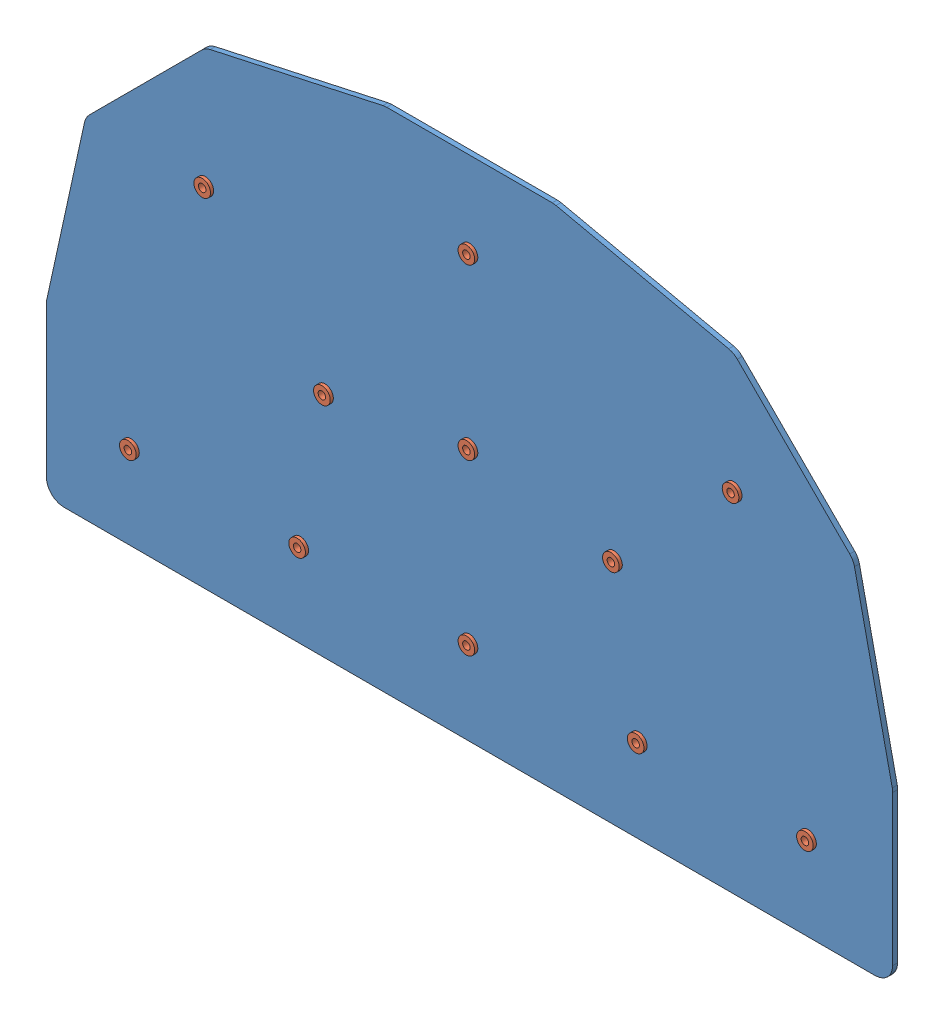
SolidWorks assembly W_w_rivets170927, configuration Default. Lengths in mm.
Overall size (269.88 161.93 7).
12 component instances, 2 part files, 22 mates.
Components (placement in the parent):
- 2inch_cross170927-1: 2inch_cross170927 [Default] at (105.4417 101.5098 231.3869) size (269.88 161.93 1.59)
- 0.3125 rivet170927-1: 0.3125 rivet170927 [Default] at (-2.5083 128.4973 232.9744) x (1 0 0) z (0 -1 0) size (5.3 7 5.3)
- 0.3125 rivet170927-2: 0.3125 rivet170927 [Default] at (21.2051 212.7339 232.9744) x (0.987351 0.158553 0) z (0.158553 -0.987351 0) size (5.3 7 5.3)
- 0.3125 rivet170927-3: 0.3125 rivet170927 [Default] at (59.3712 174.5679 232.9744) x (0.959125 0.282984 0) z (0.282984 -0.959125 0) size (5.3 7 5.3)
- 0.3125 rivet170927-4: 0.3125 rivet170927 [Default] at (51.4667 128.4973 232.9744) x (0.928571 0.371154 0) z (0.371154 -0.928571 0) size (5.3 7 5.3)
- 0.3125 rivet170927-5: 0.3125 rivet170927 [Default] at (105.4417 128.4973 232.9744) x (0.906989 0.421154 0) z (0.421154 -0.906989 0) size (5.3 7 5.3)
- 0.3125 rivet170927-6: 0.3125 rivet170927 [Default] at (105.4417 182.4723 232.9744) x (0.902849 0.429957 0) z (0.429957 -0.902849 0) size (5.3 7 5.3)
- 0.3125 rivet170927-7: 0.3125 rivet170927 [Default] at (105.4417 236.4473 232.9744) x (0.919615 0.39282 0) z (0.39282 -0.919615 0) size (5.3 7 5.3)
- 0.3125 rivet170927-8: 0.3125 rivet170927 [Default] at (151.5122 174.5679 232.9744) x (0.952324 0.305088 0) z (0.305088 -0.952324 0) size (5.3 7 5.3)
- 0.3125 rivet170927-9: 0.3125 rivet170927 [Default] at (159.4167 128.4973 232.9744) x (0.985697 0.168526 0) z (0.168526 -0.985697 0) size (5.3 7 5.3)
- 0.3125 rivet170927-10: 0.3125 rivet170927 [Default] at (189.6783 212.7339 232.9744) x (1 0 0) z (0 -1 0) size (5.3 7 5.3)
- 0.3125 rivet170927-11: 0.3125 rivet170927 [Default] at (213.3917 128.4973 232.9744) x (0.985697 -0.168526 0) z (-0.168526 -0.985697 0) size (5.3 7 5.3)
Mates (geometry in assembly coordinates):
- Coincident1: coincident anti-aligned: plane of 2inch_cross170927-1 through (234.8229 107.0661 232.9744) normal (0 0 1); plane of 0.3125 rivet170927-1 through (-4.1583 128.4973 232.9744) normal (0 0 -1)
- Concentric1: concentric anti-aligned: circle of 2inch_cross170927-1; circle of 0.3125 rivet170927-1
- Coincident2: coincident anti-aligned: plane of 2inch_cross170927-1 through (234.8229 107.0661 232.9744) normal (0 0 1); plane of 0.3125 rivet170927-2 through (19.5759 212.4723 232.9744) normal (0 0 -1)
- Concentric2: concentric anti-aligned: circle of 2inch_cross170927-1; circle of 0.3125 rivet170927-2
- Coincident3: coincident anti-aligned: plane of 2inch_cross170927-1 through (234.8229 107.0661 232.9744) normal (0 0 1); plane of 0.3125 rivet170927-3 through (57.7886 174.1009 232.9744) normal (0 0 -1)
- Concentric3: concentric anti-aligned: circle of 2inch_cross170927-1; circle of 0.3125 rivet170927-3
- Coincident4: coincident anti-aligned: plane of 2inch_cross170927-1 through (234.8229 107.0661 232.9744) normal (0 0 1); plane of 0.3125 rivet170927-4 through (49.9346 127.8849 232.9744) normal (0 0 -1)
- Concentric4: concentric anti-aligned: circle of 2inch_cross170927-1; circle of 0.3125 rivet170927-4
- Coincident5: coincident anti-aligned: plane of 2inch_cross170927-1 through (234.8229 107.0661 232.9744) normal (0 0 1); plane of 0.3125 rivet170927-5 through (103.9452 127.8024 232.9744) normal (0 0 -1)
- Concentric5: concentric anti-aligned: circle of 2inch_cross170927-1; circle of 0.3125 rivet170927-5
- Coincident6: coincident anti-aligned: plane of 2inch_cross170927-1 through (234.8229 107.0661 232.9744) normal (0 0 1); plane of 0.3125 rivet170927-6 through (103.952 181.7629 232.9744) normal (0 0 -1)
- Concentric6: concentric anti-aligned: circle of 2inch_cross170927-1; circle of 0.3125 rivet170927-6
- Coincident7: coincident anti-aligned: plane of 2inch_cross170927-1 through (234.8229 107.0661 232.9744) normal (0 0 1); plane of 0.3125 rivet170927-7 through (103.9243 235.7992 232.9744) normal (0 0 -1)
- Concentric7: concentric anti-aligned: circle of 2inch_cross170927-1; circle of 0.3125 rivet170927-7
- Coincident8: coincident anti-aligned: plane of 2inch_cross170927-1 through (234.8229 107.0661 232.9744) normal (0 0 1); plane of 0.3125 rivet170927-8 through (149.9409 174.0645 232.9744) normal (0 0 -1)
- Concentric8: concentric anti-aligned: circle of 2inch_cross170927-1; circle of 0.3125 rivet170927-8
- Coincident9: coincident anti-aligned: plane of 2inch_cross170927-1 through (234.8229 107.0661 232.9744) normal (0 0 1); plane of 0.3125 rivet170927-9 through (157.7903 128.2192 232.9744) normal (0 0 -1)
- Concentric9: concentric anti-aligned: circle of 2inch_cross170927-1; circle of 0.3125 rivet170927-9
- Coincident10: coincident anti-aligned: plane of 2inch_cross170927-1 through (234.8229 107.0661 232.9744) normal (0 0 1); plane of 0.3125 rivet170927-10 through (188.0283 212.7339 232.9744) normal (0 0 -1)
- Concentric10: concentric anti-aligned: circle of 2inch_cross170927-1; circle of 0.3125 rivet170927-10
- Coincident11: coincident anti-aligned: plane of 2inch_cross170927-1 through (234.8229 107.0661 232.9744) normal (0 0 1); plane of 0.3125 rivet170927-11 through (211.7653 128.7754 232.9744) normal (0 0 -1)
- Concentric11: concentric anti-aligned: circle of 2inch_cross170927-1; circle of 0.3125 rivet170927-11
